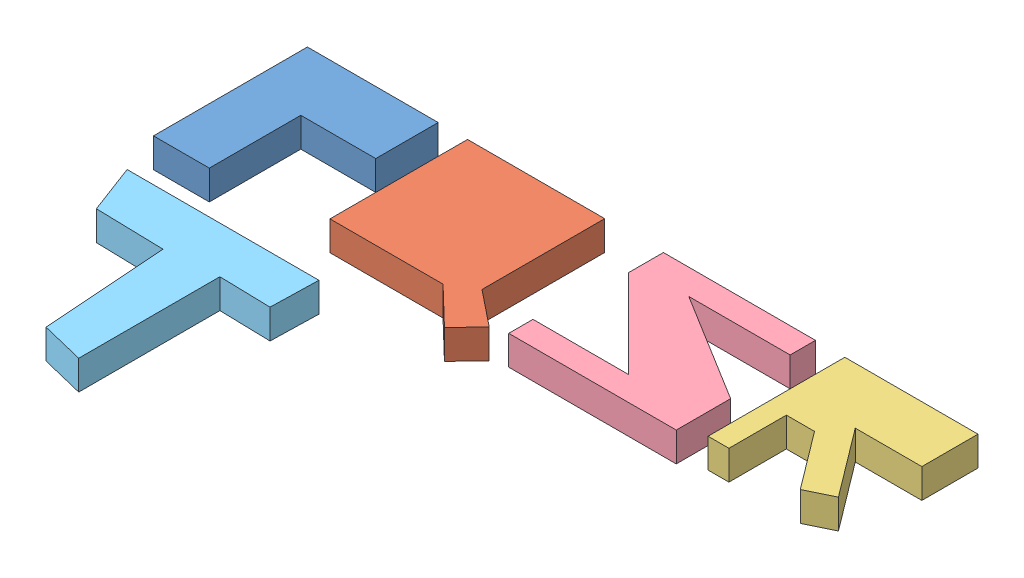
SolidWorks assembly PQRST, configuration Default. Lengths in mm.
Overall size (228.52 10 131.22).
6 component instances, 5 part files, 3 mates.
Components (placement in the parent):
- PQRS-1: PQRS [Default] at origin size (228.52 10 59.43)
  - P-1: P [Default] at origin size (44.57 10 52.46)
  - Q-1: Q [Default] at (54.569 0 -5.5748) size (59.05 10 59.43)
  - R-1: R [Default] at (183.144 0 -5.8481) size (45.38 10 46.61)
  - S-1: S [Default] at (173.144 0 -52.4562) size (57.09 10 50.2)
- T-1: T [Default] at (5.4426 0 14.4252) x (0.99969 0 0.024896) z (-0.024896 0 0.99969) size (65.35 10 64.36)
Mates (geometry in assembly coordinates):
- Coincident1: coincident: plane of PQRS-1/Q-1 through (54.569 10 -5.5748) normal (0 1 0); plane of T-1 through (-1.5303 10 14.4252) normal (0 1 0)
- Distance1: distance = 20 mm: plane of PQRS-1/Q-1 through (93.1016 10 -5.5748) normal (0 0 1); plane of T-1 through (5.4426 10 14.4252) normal (0 0 -1)
- Coincident5: coincident: point of PQRS-1/P-1; line of T-1 through (5.4426 0 14.4252) axis (0.353006 0 0.935621)
